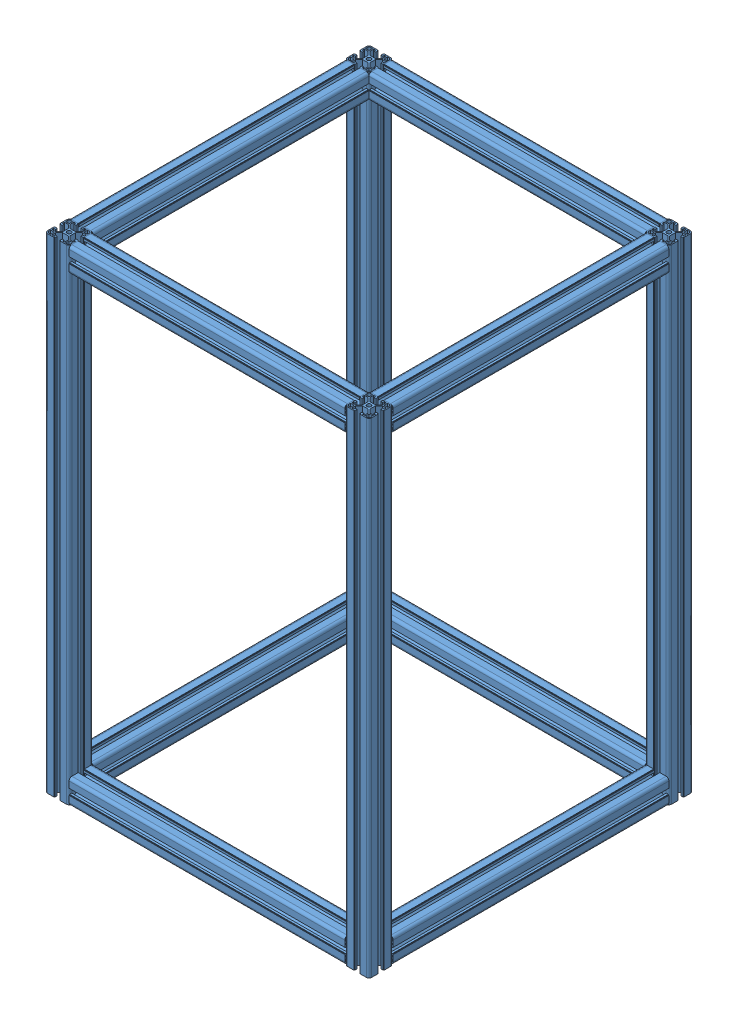
SolidWorks assembly Frame, configuration Default. Lengths in mm.
Overall size (535 800 535).
12 component instances, 1 part files, 38 mates.
Components (placement in the parent):
- 4040 Aluminium extrusion-1: 4040 Aluminium extrusion [Lenght 800mm] at (-247.5 0 -247.5) x (-1 0 0) z (0 1 0) size (40 40 800)
- 4040 Aluminium extrusion-2: 4040 Aluminium extrusion [Lenght 800mm] at (247.5 0 -247.5) x (0 0 -1) z (0 1 0) size (40 40 800)
- 4040 Aluminium extrusion-3: 4040 Aluminium extrusion [Lenght 800mm] at (247.5 0 247.5) x (0 0 1) z (0 1 0) size (40 40 800)
- 4040 Aluminium extrusion-4: 4040 Aluminium extrusion [Lenght 800mm] at (-247.5 0 247.5) x (0 0 -1) z (0 1 0) size (40 40 800)
- 4040 Aluminium extrusion-5: 4040 Aluminium extrusion [455] at (247.5 780 -227.5) size (40 40 455)
- 4040 Aluminium extrusion-6: 4040 Aluminium extrusion [455] at (247.5 20 -227.5) size (40 40 455)
- 4040 Aluminium extrusion-7: 4040 Aluminium extrusion [455] at (-227.5 20 -247.5) x (0 0 -1) z (1 0 0) size (40 40 455)
- 4040 Aluminium extrusion-11: 4040 Aluminium extrusion [455] at (-247.5 20 -227.5) size (40 40 455)
- 4040 Aluminium extrusion-12: 4040 Aluminium extrusion [455] at (-247.5 780 -227.5) size (40 40 455)
- 4040 Aluminium extrusion-13: 4040 Aluminium extrusion [455] at (-227.5 20 247.5) x (0 0 -1) z (1 0 0) size (40 40 455)
- 4040 Aluminium extrusion-14: 4040 Aluminium extrusion [455] at (-227.5 780 247.5) x (0 0 -1) z (1 0 0) size (40 40 455)
- 4040 Aluminium extrusion-15: 4040 Aluminium extrusion [455] at (-227.5 780 -247.5) x (0 0 -1) z (1 0 0) size (40 40 455)
Mates (geometry in assembly coordinates):
- Coincident2: coincident anti-aligned: plane of 4040 Aluminium extrusion-3 through (598.2058 0 247.5) normal (0 -1 0)
- Coincident3: coincident anti-aligned: plane of 4040 Aluminium extrusion-13 through (578.2058 0 247.5) normal (0 -1 0)
- Coincident4: coincident anti-aligned: plane of 4040 Aluminium extrusion-6 through (598.2058 0 227.5) normal (0 -1 0)
- Coincident6: coincident anti-aligned: plane of 4040 Aluminium extrusion-4 through (103.2058 0 247.5) normal (0 -1 0)
- Coincident7: coincident anti-aligned: plane of 4040 Aluminium extrusion-11 through (103.2058 0 227.5) normal (0 -1 0)
- Coincident8: coincident anti-aligned: plane of 4040 Aluminium extrusion-2 through (598.2058 0 -247.5) normal (0 -1 0)
- Coincident9: coincident anti-aligned: plane of 4040 Aluminium extrusion-7 through (578.2058 0 -247.5) normal (0 -1 0)
- Coincident10: coincident anti-aligned: plane of 4040 Aluminium extrusion-1 through (103.2058 0 -247.5) normal (0 -1 0)
- Coincident11: coincident anti-aligned: plane of 4040 Aluminium extrusion-3 through (578.2058 800 247.5) normal (-1 0 0); plane of 4040 Aluminium extrusion-13 through (578.2058 20 247.5) normal (1 0 0)
- Coincident12: coincident anti-aligned: plane of 4040 Aluminium extrusion-3 through (598.2058 800 227.5) normal (0 0 -1); plane of 4040 Aluminium extrusion-6 through (598.2058 20 227.5) normal (0 0 1)
- Coincident13: coincident anti-aligned: plane of 4040 Aluminium extrusion-2 through (598.2058 800 -227.5) normal (0 0 1); plane of 4040 Aluminium extrusion-6 through (598.2058 20 -227.5) normal (0 0 -1)
- Coincident14: coincident anti-aligned: plane of 4040 Aluminium extrusion-2 through (578.2058 800 -247.5) normal (-1 0 0); plane of 4040 Aluminium extrusion-7 through (578.2058 20 -247.5) normal (1 0 0)
- Coincident15: coincident anti-aligned: plane of 4040 Aluminium extrusion-1 through (123.2058 800 -247.5) normal (1 0 0); plane of 4040 Aluminium extrusion-7 through (123.2058 20 -247.5) normal (-1 0 0)
- Coincident16: coincident anti-aligned: plane of 4040 Aluminium extrusion-1 through (103.2058 800 -227.5) normal (0 0 1); plane of 4040 Aluminium extrusion-11 through (103.2058 20 -227.5) normal (0 0 -1)
- Coincident17: coincident anti-aligned: plane of 4040 Aluminium extrusion-4 through (103.2058 800 227.5) normal (0 0 -1); plane of 4040 Aluminium extrusion-11 through (103.2058 20 227.5) normal (0 0 1)
- Coincident18: coincident anti-aligned: plane of 4040 Aluminium extrusion-4 through (123.2058 800 247.5) normal (1 0 0); plane of 4040 Aluminium extrusion-13 through (123.2058 20 247.5) normal (-1 0 0)
- Coincident19: coincident aligned: plane of 4040 Aluminium extrusion-4 through (103.2058 800 267.5) normal (0 0 1); plane of 4040 Aluminium extrusion-13 through (578.2058 20 267.5) normal (0 0 1)
- Coincident20: coincident aligned: plane of 4040 Aluminium extrusion-3 through (598.2058 800 267.5) normal (0 0 1); plane of 4040 Aluminium extrusion-13 through (578.2058 20 267.5) normal (0 0 1)
- Coincident21: coincident aligned: plane of 4040 Aluminium extrusion-13 through (578.2058 20 267.5) normal (0 0 1); plane of 4040 Aluminium extrusion-14 through (578.2058 780 267.5) normal (0 0 1)
- Coincident22: coincident aligned: plane of 4040 Aluminium extrusion-4 through (83.2058 800 247.5) normal (-1 0 0); plane of 4040 Aluminium extrusion-11 through (83.2058 20 227.5) normal (-1 0 0)
- Coincident23: coincident aligned: plane of 4040 Aluminium extrusion-1 through (83.2058 800 -247.5) normal (-1 0 0); plane of 4040 Aluminium extrusion-11 through (83.2058 20 227.5) normal (-1 0 0)
- Coincident24: coincident aligned: plane of 4040 Aluminium extrusion-11 through (83.2058 20 227.5) normal (-1 0 0); plane of 4040 Aluminium extrusion-12 through (83.2058 780 227.5) normal (-1 0 0)
- Coincident25: coincident anti-aligned: plane of 4040 Aluminium extrusion-1 through (103.2058 800 -227.5) normal (0 0 1); plane of 4040 Aluminium extrusion-12 through (103.2058 780 -227.5) normal (0 0 -1)
- Coincident29: coincident aligned: plane of 4040 Aluminium extrusion-4 through (103.2058 800 247.5) normal (0 1 0); plane of 4040 Aluminium extrusion-14 through (578.2058 800 247.5) normal (0 1 0)
- Coincident30: coincident aligned: plane of 4040 Aluminium extrusion-4 through (103.2058 800 247.5) normal (0 1 0); plane of 4040 Aluminium extrusion-12 through (103.2058 800 227.5) normal (0 1 0)
- Coincident31: coincident aligned: plane of 4040 Aluminium extrusion-4 through (103.2058 800 247.5) normal (0 1 0); plane of 4040 Aluminium extrusion-5 through (598.2058 800 227.5) normal (0 1 0)
- Coincident32: coincident aligned: plane of 4040 Aluminium extrusion-4 through (103.2058 800 247.5) normal (0 1 0); plane of 4040 Aluminium extrusion-15 through (578.2058 800 -247.5) normal (0 1 0)
- Coincident33: coincident aligned: plane of 4040 Aluminium extrusion-1 through (103.2058 800 -267.5) normal (0 0 -1); plane of 4040 Aluminium extrusion-7 through (578.2058 20 -267.5) normal (0 0 -1)
- Coincident34: coincident aligned: plane of 4040 Aluminium extrusion-2 through (598.2058 800 -267.5) normal (0 0 -1); plane of 4040 Aluminium extrusion-7 through (578.2058 20 -267.5) normal (0 0 -1)
- Coincident35: coincident aligned: plane of 4040 Aluminium extrusion-7 through (578.2058 20 -267.5) normal (0 0 -1); plane of 4040 Aluminium extrusion-15 through (578.2058 780 -267.5) normal (0 0 -1)
- Coincident36: coincident aligned: plane of 4040 Aluminium extrusion-3 through (618.2058 800 247.5) normal (1 0 0); plane of 4040 Aluminium extrusion-6 through (618.2058 20 227.5) normal (1 0 0)
- Coincident37: coincident aligned: plane of 4040 Aluminium extrusion-2 through (618.2058 800 -247.5) normal (1 0 0); plane of 4040 Aluminium extrusion-6 through (618.2058 20 227.5) normal (1 0 0)
- Coincident38: coincident aligned: plane of 4040 Aluminium extrusion-5 through (618.2058 780 227.5) normal (1 0 0); plane of 4040 Aluminium extrusion-6 through (618.2058 20 227.5) normal (1 0 0)
- Coincident39: coincident anti-aligned: plane of 4040 Aluminium extrusion-3 through (578.2058 800 247.5) normal (-1 0 0); plane of 4040 Aluminium extrusion-14 through (578.2058 780 247.5) normal (1 0 0)
- Coincident40: coincident anti-aligned: plane of 4040 Aluminium extrusion-3 through (598.2058 800 227.5) normal (0 0 -1); plane of 4040 Aluminium extrusion-5 through (598.2058 780 227.5) normal (0 0 1)
- Coincident41: coincident anti-aligned: plane of 4040 Aluminium extrusion-2 through (578.2058 800 -247.5) normal (-1 0 0); plane of 4040 Aluminium extrusion-15 through (578.2058 780 -247.5) normal (1 0 0)
- Symmetric1: symmetric aligned: plane of 4040 Aluminium extrusion-7 through (578.2058 20 -267.5) normal (0 0 -1); plane of 4040 Aluminium extrusion-13 through (578.2058 20 267.5) normal (0 0 1)
- Symmetric2: symmetric aligned: plane of 4040 Aluminium extrusion-6 through (618.2058 20 227.5) normal (1 0 0); plane of 4040 Aluminium extrusion-11 through (83.2058 20 227.5) normal (-1 0 0)
